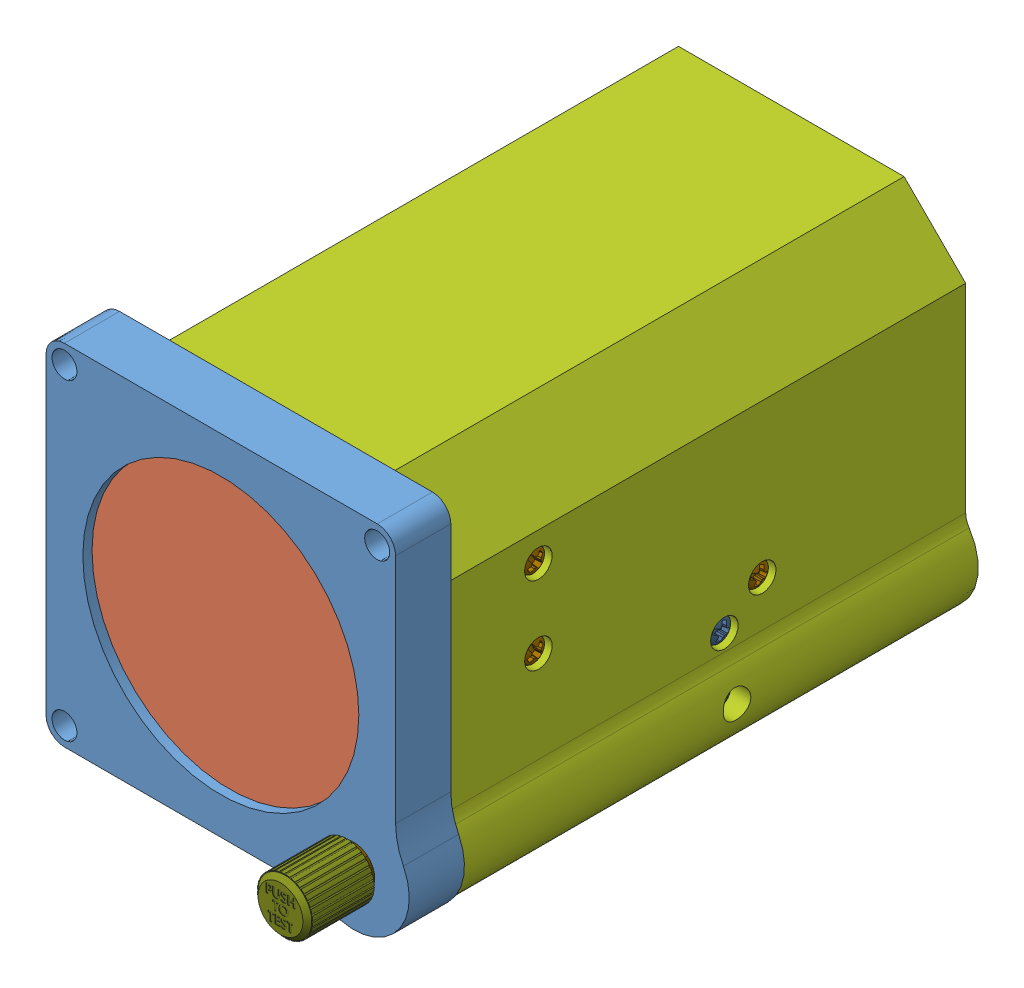
SolidWorks assembly Radar Altimeter, configuration Default. Lengths in mm.
Overall size (63.84 62.68 111.12).
82 component instances, 36 part files, 162 mates.
Components (placement in the parent):
- Radar Altimeter Bezel-1: Radar Altimeter Bezel [Default] at origin size (62.68 62.68 9.53)
- Airspeed Indicator Cover Glass-1: Airspeed Indicator Cover Glass [Default] at (0 0 6.35) size (49.91 49.91 1.59)
- Radar Altimeter Needle Mask-1: Radar Altimeter Needle Mask [Default] at (0 0 3.175) size (49.91 49.91 3.17)
- Radar Altimeter Dial Face-1: Radar Altimeter Dial Face [Default] at (0 0 -3.175) size (47.65 47.65 1.59)
- Radar Altimeter Stepper Mount-1: Radar Altimeter Stepper Mount [Default] at (0 0 -3.175) x (-1 0 0) z (0 0 -1) size (54.44 52.43 10.49)
- Radar Altimeter Stepper Standoff-1: Radar Altimeter Stepper Standoff [Default] at (0 0 -3.175) x (-1 0 0) z (0 0 -1) size (56.62 55.62 12.7)
- Radar Altimeter Case-1: Radar Altimeter Case [Default] x (-1 0 0) z (0 0 -1) size (62.36 61.36 88.9)
- Radar Altimeter Indicator Pointer-1: Radar Altimeter Indicator Pointer [Default] at origin size (6.35 21.41 0.76)
- VID29-02-1: VID29-02 [Default] at (0 6 -17.188) x (1 0 0) z (0 -1 0) size (31.7 22.35 29.3)
- MD-80PL100-1: MD-80PL100 [Default] at (0 -8.7668 -85.09) x (0 0 -1) z (1 0 0) size (21.05 14 25)
- MD-40PL100-1: MD-40PL100 [Default] at (0 9.7828 -85.09) x (0 0 -1) z (1 0 0) size (21.05 14 25)
- SMB 200 RTP-1: SMB 200 RTP [Default] at (-9.525 0 -7.3279) x (0 0 -1) z (1 0 0) size (7.24 4.9 4.98)
- LTW-420D7-1: LTW-420D7 [Default] at (-9.525 0 -6.5659) x (-1 0 0) z (0 1 0) size (3.4 10.4 3.8)
- SMB 200 GTP-1: SMB 200 GTP [Default] at (9.525 0 -7.3279) x (0 0 -1) z (0.923728 0.383049 0) size (7.24 4.9 4.98)
- LTW-420D7-2: LTW-420D7 [Default] at (9.525 0 -6.5659) x (-1 0 0) z (0 1 0) size (3.4 10.4 3.8)
- Radar Altimeter Limit Indexer Ring-1: Radar Altimeter Limit Indexer Ring [Default] x (0 -1 0) z (0 0 1) size (54.8 54.8 4.19)
- Radar Altimeter Knob-1: Radar Altimeter Knob [Default] at (22.9895 -22.9895 9.525) x (1 0 0) z (0 -1 0) size (9.52 11.43 9.52)
- Radar Altimeter Limit Shaft Gear-2: Radar Altimeter Limit Shaft Gear [Default] at (22.9895 -22.9895 -3.1496) x (-1 0 0) z (0 0 1) size (13.89 13.89 6.35)
- 634070_SERVOCITY_.250 X 2.250 D-SHAFT-1: 634070_SERVOCITY_.250 X 2.250 D-SHAFT [Default] at (22.9895 -22.9895 -9.398) x (-1 0 0) z (0 -1 0) size (6.34 57.15 5.59)
- 6630S0D-C28-A103 -1: 6630S0D-C28-A103  [Default] at (13.037 -15.1003 -67.0052) size (22.23 22.23 41.93)
- 615242_SERVOCITY_GEAR_.250 SHAFT-1: 615242_SERVOCITY_GEAR_.250 SHAFT [Default] at (-12.7042 12.8762 11.5787) x (-1 0 0) z (0 0 -1) size (14.29 14.29 12.89)
  - 615242_Gear Blank-1: 615242_Gear Blank [Default] at (-35.6936 -35.8657 43.2017) size (14.29 14.29 12.7)
  - 632134_91375A436-1: 632134_91375A436 [Default] at (-35.6936 -31.9694 40.0267) x (0.866032 0 0.499989) z (0 1 0) size (4.98 4.83 3.31)
- 615242_SERVOCITY_GEAR_.250 SHAFT-2: 615242_SERVOCITY_GEAR_.250 SHAFT [Default] at (48.7306 20.7654 -81.1747) size (14.29 14.29 12.89)
  - 615242_Gear Blank-1: 615242_Gear Blank [Default] at (-35.6936 -35.8657 43.2017) size (14.29 14.29 12.7)
  - 632134_91375A436-1: 632134_91375A436 [Default] at (-35.6936 -31.9694 40.0267) x (0.866032 0 0.499989) z (0 1 0) size (4.98 4.83 3.31)
- 1692K530_TYPE 302 SS CONICAL COMPRESSION SPRING-1: 1692K530_TYPE 302 SS CONICAL COMPRESSION SPRING [1692K53] at (22.9895 -22.9895 -8.824) x (-0.923728 -0.383049 0) z (-0.383049 0.923728 0) size (11.69 5.68 11.52)
- 7658K170_SUBMINIATURE SNAP-ACTING SWITCH-2: 7658K170_SUBMINIATURE SNAP-ACTING SWITCH [Default] at (23.9673 -17.7927 -49.6316) x (0 1 0) z (1 0 0) size (19.99 14.86 6.5)
- Radar Altimeter Pot Mount-1: Radar Altimeter Pot Mount [Default] at (13.037 -15.1003 -56.9722) size (25.29 22.23 12.7)
- 90760A005_ZINC PLATED STEEL NARROW HEX NUT-1: 90760A005_ZINC PLATED STEEL NARROW HEX NUT [Default] at (19.9223 -13.0048 -47.2694) x (0 -0.557681 -0.830056) z (0 0.830056 -0.557681) size (4.76 1.76 5.5)
- 90760A005_ZINC PLATED STEEL NARROW HEX NUT-2: 90760A005_ZINC PLATED STEEL NARROW HEX NUT [Default] at (19.9223 -22.6441 -47.2694) x (0 -0.557681 -0.830056) z (0 0.830056 -0.557681) size (4.76 1.76 5.5)
- 93365A110_BRASS HEAT-SET INSERT FOR PLASTICS_2-56-6: 93365A110_BRASS HEAT-SET INSERT FOR PLASTICS_2-56 [Default] at (5.0486 -26.2128 -47.4472) x (-0.133778 0 -0.991011) z (-0.991011 0 0.133778) size (3.58 3.09 3.58)
- 90272A077_ZINC-PLTD STL PAN HEAD PHILLIPS MACHINE SCREW_2-56 X .250-5: 90272A077_ZINC-PLTD STL PAN HEAD PHILLIPS MACHINE SCREW_2-56 X .250 [90272A077] at (5.0486 -20.9042 -47.4472) x (0.315604 0 0.948891) z (0 -1 0) size (4.24 4.24 7.94)
- 93365A110_BRASS HEAT-SET INSERT FOR PLASTICS_2-56-19: 93365A110_BRASS HEAT-SET INSERT FOR PLASTICS_2-56 [Default] at (27.2185 -7.9566 -53.7972) x (0 -0.1618 -0.986824) z (0 -0.986824 0.1618) size (3.58 3.09 3.58)
- 90272A077_ZINC-PLTD STL PAN HEAD PHILLIPS MACHINE SCREW_2-56 X .250-7: 90272A077_ZINC-PLTD STL PAN HEAD PHILLIPS MACHINE SCREW_2-56 X .250 [90272A077] at (21.9099 -7.9566 -53.7972) x (0 0.34236 0.939569) z (1 0 0) size (4.24 4.24 7.94)
- 90272A079_ZINC-PLTD STL PAN HEAD PHILLIPS MACHINE SCREW_2-56 X .375-11: 90272A079_ZINC-PLTD STL PAN HEAD PHILLIPS MACHINE SCREW_2-56 X .375 [90272A079] at (18.7349 -13.0048 -47.2694) x (0 -0.383049 -0.923728) z (1 0 0) size (4.24 4.24 11.11)
- 90272A079_ZINC-PLTD STL PAN HEAD PHILLIPS MACHINE SCREW_2-56 X .375-12: 90272A079_ZINC-PLTD STL PAN HEAD PHILLIPS MACHINE SCREW_2-56 X .375 [90272A079] at (18.7349 -22.6441 -47.2694) x (0 -0.231744 -0.972777) z (1 0 0) size (4.24 4.24 11.11)
- Hitec Ultra Nano HS-35HD-1: Hitec Ultra Nano HS-35HD [Default] at (1.8656 -35.3668 -24.7523) x (0.579498 -0.814974 0) z (0 0 1) size (25.28 28.66 21.31)
  - Hitec HS-35HD Ultra Nano Servo-1: Hitec HS-35HD Ultra Nano Servo [Default] at (-26.6145 -7.4096 -0.762) x (0.579498 0.814974 0) z (0 0 1) size (26.49 7.75 19.66)
  - servo horn-1: servo horn [Default] at (-27.1584 -1.5999 19.9898) x (0.728983 0.684532 0) z (-0.684532 0.728983 0) size (16.38 3.21 16.38)
  - screw-1: screw [Default] at (-27.1584 -1.5999 20.5457) x (0.992399 -0.123063 0) z (0 0 1) size (2.9 2.9 4.67)
- Radar Altimeter OFF Flag-2: Radar Altimeter OFF Flag [Default] at (0 0 -3.175) x (-1 0 0) z (0 0 -1) size (30.35 16.38 1.59)
- 92671A115_BRASS HEX NUT-1: 92671A115_BRASS HEX NUT [92671A115] at (1.143 -14.1605 -8.2297) x (0.956133 -0.292934 0) z (-0.292934 -0.956133 0) size (3.97 1.51 4.58)
- 92671A115_BRASS HEX NUT-2: 92671A115_BRASS HEX NUT [92671A115] at (-21.59 -14.1605 -8.2297) x (0.990484 -0.137631 0) z (-0.137631 -0.990484 0) size (3.97 1.51 4.58)
- 91772A061_18-8 SS PAN HEAD PHILLIPS MACHINE SCREW_#0-80 X .2812-1: 91772A061_18-8 SS PAN HEAD PHILLIPS MACHINE SCREW_#0-80 X .2812 [91772A061] at (-21.59 -14.1605 -7.0421) x (-0.923728 -0.383049 0) z (0 0 -1) size (2.95 2.95 8.26)
- 91772A061_18-8 SS PAN HEAD PHILLIPS MACHINE SCREW_#0-80 X .2812-2: 91772A061_18-8 SS PAN HEAD PHILLIPS MACHINE SCREW_#0-80 X .2812 [91772A061] at (1.143 -14.1605 -7.0421) x (-0.85131 -0.524663 0) z (0 0 -1) size (2.95 2.95 8.26)
- 93365A110_BRASS HEAT-SET INSERT FOR PLASTICS_2-56-1: 93365A110_BRASS HEAT-SET INSERT FOR PLASTICS_2-56 [Default] at (20.6092 18.5346 -8.825) x (-0.984497 -0.175399 0) z (0.175399 -0.984497 0) size (3.58 3.09 3.58)
- 93365A110_BRASS HEAT-SET INSERT FOR PLASTICS_2-56-18: 93365A110_BRASS HEAT-SET INSERT FOR PLASTICS_2-56 [Default] at (-20.6092 -4.5 -8.825) x (-0.984497 -0.175399 0) z (0.175399 -0.984497 0) size (3.58 3.09 3.58)
- 93365A110_BRASS HEAT-SET INSERT FOR PLASTICS_2-56-4: 93365A110_BRASS HEAT-SET INSERT FOR PLASTICS_2-56 [Default] at (-20.6092 18.5346 -8.825) x (-0.984497 -0.175399 0) z (0.175399 -0.984497 0) size (3.58 3.09 3.58)
- 90272A079_ZINC-PLTD STL PAN HEAD PHILLIPS MACHINE SCREW_2-56 X .375-4: 90272A079_ZINC-PLTD STL PAN HEAD PHILLIPS MACHINE SCREW_2-56 X .375 [90272A079] at (20.6092 18.5346 -4.0752) x (-0.923728 -0.383049 0) z (0 0 -1) size (4.24 4.24 11.11)
- 90272A079_ZINC-PLTD STL PAN HEAD PHILLIPS MACHINE SCREW_2-56 X .375-10: 90272A079_ZINC-PLTD STL PAN HEAD PHILLIPS MACHINE SCREW_2-56 X .375 [90272A079] at (-20.6092 -4.5 -4.0752) x (-0.923728 -0.383049 0) z (0 0 -1) size (4.24 4.24 11.11)
- 90272A079_ZINC-PLTD STL PAN HEAD PHILLIPS MACHINE SCREW_2-56 X .375-5: 90272A079_ZINC-PLTD STL PAN HEAD PHILLIPS MACHINE SCREW_2-56 X .375 [90272A079] at (-20.6092 18.5346 -4.0752) x (-0.923728 -0.383049 0) z (0 0 -1) size (4.24 4.24 11.11)
- 93365A110_BRASS HEAT-SET INSERT FOR PLASTICS_2-56-2: 93365A110_BRASS HEAT-SET INSERT FOR PLASTICS_2-56 [Default] at (-27.2185 13.456 -15.175) x (0 -0.185827 -0.982583) z (0 0.982583 -0.185827) size (3.58 3.09 3.58)
- 90272A077_ZINC-PLTD STL PAN HEAD PHILLIPS MACHINE SCREW_2-56 X .250-4: 90272A077_ZINC-PLTD STL PAN HEAD PHILLIPS MACHINE SCREW_2-56 X .250 [90272A077] at (-21.9099 13.456 -15.175) x (0 0 1) z (-1 0 0) size (4.24 4.24 7.94)
- 93365A110_BRASS HEAT-SET INSERT FOR PLASTICS_2-56-15: 93365A110_BRASS HEAT-SET INSERT FOR PLASTICS_2-56 [Default] at (25.4059 16.1162 0) x (0.880537 0.473977 0) z (-0.473977 0.880537 0) size (3.58 3.09 3.58)
- 93365A110_BRASS HEAT-SET INSERT FOR PLASTICS_2-56-17: 93365A110_BRASS HEAT-SET INSERT FOR PLASTICS_2-56 [Default] at (-25.4059 16.1162 0) x (0.880537 0.473977 0) z (-0.473977 0.880537 0) size (3.58 3.09 3.58)
- 90272A079_ZINC-PLTD STL PAN HEAD PHILLIPS MACHINE SCREW_2-56 X .375-7: 90272A079_ZINC-PLTD STL PAN HEAD PHILLIPS MACHINE SCREW_2-56 X .375 [90272A079] at (25.4059 16.1162 3.5448) x (0.258691 -0.96596 0) z (0 0 -1) size (4.24 4.24 11.11)
- 90272A079_ZINC-PLTD STL PAN HEAD PHILLIPS MACHINE SCREW_2-56 X .375-9: 90272A079_ZINC-PLTD STL PAN HEAD PHILLIPS MACHINE SCREW_2-56 X .375 [90272A079] at (-25.4059 16.1162 3.5448) x (0.258691 -0.96596 0) z (0 0 -1) size (4.24 4.24 11.11)
- 93365A110_BRASS HEAT-SET INSERT FOR PLASTICS_2-56-20: 93365A110_BRASS HEAT-SET INSERT FOR PLASTICS_2-56 [Default] at (-27.2185 0 -15.175) x (0 -0.027685 -0.999617) z (0 0.999617 -0.027685) size (3.58 3.09 3.58)
- 90272A077_ZINC-PLTD STL PAN HEAD PHILLIPS MACHINE SCREW_2-56 X .250-8: 90272A077_ZINC-PLTD STL PAN HEAD PHILLIPS MACHINE SCREW_2-56 X .250 [90272A077] at (-21.9099 0 -15.175) x (0 -0.158553 0.987351) z (-1 0 0) size (4.24 4.24 7.94)
- 93365A110_BRASS HEAT-SET INSERT FOR PLASTICS_2-56-21: 93365A110_BRASS HEAT-SET INSERT FOR PLASTICS_2-56 [Default] at (-14.4616 -26.2128 -15.175) x (-0.396628 0 -0.91798) z (-0.91798 0 0.396628) size (3.58 3.09 3.58)
- 90272A077_ZINC-PLTD STL PAN HEAD PHILLIPS MACHINE SCREW_2-56 X .250-9: 90272A077_ZINC-PLTD STL PAN HEAD PHILLIPS MACHINE SCREW_2-56 X .250 [90272A077] at (-14.4616 -20.9042 -15.175) x (0.560305 0 0.828287) z (0 -1 0) size (4.24 4.24 7.94)
- 93365A110_BRASS HEAT-SET INSERT FOR PLASTICS_2-56-22: 93365A110_BRASS HEAT-SET INSERT FOR PLASTICS_2-56 [Default] at (11.1826 -26.2128 -13.389) x (-0.600122 0 -0.799909) z (-0.799909 0 0.600122) size (3.58 3.09 3.58)
- 90272A077_ZINC-PLTD STL PAN HEAD PHILLIPS MACHINE SCREW_2-56 X .250-10: 90272A077_ZINC-PLTD STL PAN HEAD PHILLIPS MACHINE SCREW_2-56 X .250 [90272A077] at (11.1826 -20.9042 -13.389) x (0.738314 0 0.674458) z (0 -1 0) size (4.24 4.24 7.94)
- 93365A110_BRASS HEAT-SET INSERT FOR PLASTICS_2-56-23: 93365A110_BRASS HEAT-SET INSERT FOR PLASTICS_2-56 [Default] at (27.2185 13.456 -15.175) x (0 -0.622542 -0.782586) z (0 -0.782586 0.622542) size (3.58 3.09 3.58)
- 90272A077_ZINC-PLTD STL PAN HEAD PHILLIPS MACHINE SCREW_2-56 X .250-11: 90272A077_ZINC-PLTD STL PAN HEAD PHILLIPS MACHINE SCREW_2-56 X .250 [90272A077] at (21.9099 13.456 -15.175) x (0 0.757125 0.65327) z (1 0 0) size (4.24 4.24 7.94)
- 93365A110_BRASS HEAT-SET INSERT FOR PLASTICS_2-56-24: 93365A110_BRASS HEAT-SET INSERT FOR PLASTICS_2-56 [Default] at (27.2185 0 -15.175) x (0 -0.682826 -0.730581) z (0 -0.730581 0.682826) size (3.58 3.09 3.58)
- 90272A077_ZINC-PLTD STL PAN HEAD PHILLIPS MACHINE SCREW_2-56 X .250-12: 90272A077_ZINC-PLTD STL PAN HEAD PHILLIPS MACHINE SCREW_2-56 X .250 [90272A077] at (21.9099 0 -15.175) x (0 0.806695 0.590969) z (1 0 0) size (4.24 4.24 7.94)
- 93365A102 - INSERT, 0-80, BRASS, FOR PLASTICS-1: 93365A102 - INSERT, 0-80, BRASS, FOR PLASTICS [Default] at (-9.5 -8.7668 -85.09) x (1 0 0) z (0 -1 0) size (3.58 3.01 3.58)
- 93365A102 - INSERT, 0-80, BRASS, FOR PLASTICS-2: 93365A102 - INSERT, 0-80, BRASS, FOR PLASTICS [Default] at (9.5 -8.7668 -85.09) x (0.987351 0.158553 0) z (0.158553 -0.987351 0) size (3.58 3.01 3.58)
- 93365A102 - INSERT, 0-80, BRASS, FOR PLASTICS-4: 93365A102 - INSERT, 0-80, BRASS, FOR PLASTICS [Default] at (9.5 9.7828 -85.09) x (0.959125 0.282984 0) z (0.282984 -0.959125 0) size (3.58 3.01 3.58)
- 93365A102 - INSERT, 0-80, BRASS, FOR PLASTICS-6: 93365A102 - INSERT, 0-80, BRASS, FOR PLASTICS [Default] at (-9.5 9.7828 -85.09) x (0.928571 0.371154 0) z (0.371154 -0.928571 0) size (3.58 3.01 3.58)
- 91772A064 - PHS, 0-80 x .4375, 18-8-1: 91772A064 - PHS, 0-80 x .4375, 18-8 [91772A064] at (-9.5 9.7828 -88.2025) x (-0.994753 -0.10231 0) z (0 0 1) size (2.95 2.95 12.24)
- 91772A064 - PHS, 0-80 x .4375, 18-8-2: 91772A064 - PHS, 0-80 x .4375, 18-8 [91772A064] at (9.5 9.7828 -88.2025) x (-0.965948 -0.258737 0) z (0 0 1) size (2.95 2.95 12.24)
- 91772A064 - PHS, 0-80 x .4375, 18-8-4: 91772A064 - PHS, 0-80 x .4375, 18-8 [91772A064] at (-9.5 -8.7668 -88.2025) x (-0.92514 -0.379627 0) z (0 0 1) size (2.95 2.95 12.24)
- 91772A064 - PHS, 0-80 x .4375, 18-8-6: 91772A064 - PHS, 0-80 x .4375, 18-8 [91772A064] at (9.5 -8.7668 -88.2025) x (-0.885726 -0.464208 0) z (0 0 1) size (2.95 2.95 12.24)
- 93365A102 - INSERT, 0-80, BRASS, FOR PLASTICS-8: 93365A102 - INSERT, 0-80, BRASS, FOR PLASTICS [Default] at (13.5 6 -10.488) x (-0.173648 0.984808 0) z (-0.984808 -0.173648 0) size (3.58 3.01 3.58)
- 93365A102 - INSERT, 0-80, BRASS, FOR PLASTICS-10: 93365A102 - INSERT, 0-80, BRASS, FOR PLASTICS [Default] at (-13.5 6 -10.488) x (-0.34202 0.939693 0) z (-0.939693 -0.34202 0) size (3.58 3.01 3.58)
- 91772A064 - PHS, 0-80 x .4375, 18-8-8: 91772A064 - PHS, 0-80 x .4375, 18-8 [91772A064] at (13.5 6 -6.3755) x (0.965948 -0.258737 0) z (0 0 -1) size (2.95 2.95 12.24)
- 91772A064 - PHS, 0-80 x .4375, 18-8-10: 91772A064 - PHS, 0-80 x .4375, 18-8 [91772A064] at (-13.5 6 -6.3755) x (-0.92514 0.379627 0) z (0 0 -1) size (2.95 2.95 12.24)
- 93365A110_BRASS HEAT-SET INSERT FOR PLASTICS_2-56-28: 93365A110_BRASS HEAT-SET INSERT FOR PLASTICS_2-56 [Default] at (20.6092 -4.5 -8.825) x (-0.984497 -0.175399 0) z (0.175399 -0.984497 0) size (3.58 3.09 3.58)
- 90272A079_ZINC-PLTD STL PAN HEAD PHILLIPS MACHINE SCREW_2-56 X .375-13: 90272A079_ZINC-PLTD STL PAN HEAD PHILLIPS MACHINE SCREW_2-56 X .375 [90272A079] at (20.6092 -4.5 -4.0752) x (-0.923728 -0.383049 0) z (0 0 -1) size (4.24 4.24 11.11)
Mates (geometry in assembly coordinates):
- InPlace1: in place: plane of ? through (0 0 0) normal (0 0 1); moOrthogonalPlaneRef_w of ? through (0 0 0) normal (0 1 0); plane of ? through (0 0 0) normal (1 0 0); unknown of ?
- Coincident1: coincident aligned: 
- Coincident2: coincident aligned: plane of Radar Altimeter Bezel-1 through (0 0 0) normal (0 1 0)
- Coincident3: coincident anti-aligned: plane of Radar Altimeter Bezel-1 through (0 0 0) normal (1 0 0)
- Concentric1: concentric aligned: cylinder of Radar Altimeter Bezel-1 through (0 0 81.1874) axis (0 0 -1) radius 25.3365; cylinder of Airspeed Indicator Cover Glass-1 through (0 0 7.9375) axis (0 0 -1) radius 24.9555
- Coincident1: coincident anti-aligned: plane of Radar Altimeter Bezel-1 through (0 0 7.9375) normal (0 0 -1); plane of Airspeed Indicator Cover Glass-1 through (0 0 7.9375) normal (0 0 1)
- Concentric2: concentric aligned: cylinder of Radar Altimeter Bezel-1 through (0 0 81.1874) axis (0 0 -1) radius 25.3365; cylinder of Radar Altimeter Needle Mask-1 through (0 0 6.35) axis (0 0 -1) radius 24.9555
- Concentric5: concentric aligned: cylinder of Radar Altimeter Bezel-1 through (0 0 81.1874) axis (0 0 -1) radius 25.3365; cylinder of Radar Altimeter Dial Face-1 through (0 0 -1.5875) axis (0 0 -1) radius 23.8252
- Parallel1: parallel aligned: plane of Radar Altimeter Bezel-1 through (30.1625 0 9.525) normal (1 0 0); plane of Radar Altimeter Dial Face-1 through (0 0 -3.175) normal (1 0 0)
- Coincident7: coincident anti-aligned: plane of Radar Altimeter Dial Face-1 through (0 0 -3.175) normal (0 0 -1); plane of Radar Altimeter Stepper Mount-1 through (0 0 -3.175) normal (0 0 1)
- Parallel2: parallel anti-aligned: plane of Radar Altimeter Bezel-1 through (30.1625 0 9.525) normal (1 0 0); plane of Radar Altimeter Stepper Mount-1 through (0 0 -3.175) normal (-1 0 0)
- Distance1: distance = 1.5875 mm anti-aligned: plane of Radar Altimeter Indicator Pointer-1 through (0 0 0) normal (0 0 -1); plane of Radar Altimeter Dial Face-1 through (0 0 -1.5875) normal (0 0 1)
- Width12: width anti-aligned: plane of Radar Altimeter Stepper Mount-1 through (-18.2716 26.2128 -100.9823) normal (0 1 0); plane of Radar Altimeter Stepper Mount-1 through (16.2895 -26.2128 -100.9823) normal (0 -1 0); plane of Radar Altimeter Bezel-1 through (0 -30.1625 9.525) normal (0 -1 0); plane of Radar Altimeter Bezel-1 through (0 30.1625 9.525) normal (0 1 0)
- Concentric55: concentric aligned: cone of Radar Altimeter Stepper Mount-1 through (20.6092 18.5346 -8.825) axis (0 0 1); cone of 93365A110_BRASS HEAT-SET INSERT FOR PLASTICS_2-56-1 through (20.6092 18.5346 -7.715) axis (0 0 1)
- Coincident81: coincident aligned: plane of Radar Altimeter Stepper Mount-1 through (0 -6 -8.825) normal (0 0 -1); plane of 93365A110_BRASS HEAT-SET INSERT FOR PLASTICS_2-56-1 through (22.3722 18.8487 -8.825) normal (0 0 -1)
- Concentric80: concentric anti-aligned: cylinder of SMB 200 RTP-1 through (-9.525 0 -0.0889) axis (0 0 1) radius 2.1947; cylinder of LTW-420D7-1 through (-9.525 0 -6.5659) axis (0 0 -1) radius 1.5
- Parallel31: parallel anti-aligned: plane of Radar Altimeter Bezel-1 through (0 30.1625 9.525) normal (0 1 0); plane of LTW-420D7-1 through (-10.5629 -0.1492 -10.5659) normal (0 -1 0)
- Distance7: distance = 0.762 mm aligned: plane of LTW-420D7-1 through (-9.525 0 -6.5659) normal (0 0 -1); plane of SMB 200 RTP-1 through (-9.525 -2.1844 -7.3279) normal (0 0 -1)
- Concentric81: concentric aligned: cylinder of Radar Altimeter Dial Face-1 through (-9.525 0 -1.5875) axis (0 0 1) radius 2.1829; cylinder of SMB 200 RTP-1 through (-9.525 0 -0.0889) axis (0 0 1) radius 2.4511
- Coincident113: coincident anti-aligned: plane of Radar Altimeter Dial Face-1 through (0 0 -1.5875) normal (0 0 1); plane of SMB 200 RTP-1 through (-9.525 -2.1947 -1.5875) normal (0 0 -1)
- Concentric82: concentric aligned: cylinder of Radar Altimeter Dial Face-1 through (9.525 0 -1.5875) axis (0 0 1) radius 2.1829; cylinder of SMB 200 GTP-1 through (9.525 0 -0.0889) axis (0 0 1) radius 2.1947
- Coincident114: coincident anti-aligned: plane of Radar Altimeter Dial Face-1 through (0 0 -1.5875) normal (0 0 1); plane of SMB 200 GTP-1 through (10.3657 -2.0273 -1.5875) normal (0 0 -1)
- Concentric83: concentric anti-aligned: cylinder of SMB 200 GTP-1 through (9.525 0 -0.0889) axis (0 0 1) radius 2.1947; cylinder of LTW-420D7-2 through (9.525 0 -6.5659) axis (0 0 -1) radius 1.5
- Coincident115: coincident aligned: plane of LTW-420D7-1 through (-9.525 0 -6.5659) normal (0 0 -1); plane of LTW-420D7-2 through (9.525 0 -6.5659) normal (0 0 -1)
- Coincident116: coincident aligned: plane of LTW-420D7-1 through (-8.4871 -0.1492 -10.5659) normal (0 -1 0); plane of LTW-420D7-2 through (10.5629 -0.1492 -10.5659) normal (0 -1 0)
- Coincident117: coincident anti-aligned: plane of Airspeed Indicator Cover Glass-1 through (0 0 6.35) normal (0 0 -1); plane of Radar Altimeter Needle Mask-1 through (0 0 6.35) normal (0 0 1)
- Concentric86: concentric aligned: cylinder of Radar Altimeter Needle Mask-1 through (0 0 6.35) axis (0 0 -1) radius 23.368; cylinder of Radar Altimeter Limit Indexer Ring-1 through (0 0 -1.016) axis (0 0 -1) radius 23.368
- Coincident125: coincident aligned: plane of Radar Altimeter Limit Indexer Ring-1 through (0 0 0) normal (0 0 -1); plane of Radar Altimeter Limit Shaft Gear-2 through (22.9895 -22.9895 -3.1496) normal (0 0 -1)
- Coincident129: coincident anti-aligned: plane of Radar Altimeter Bezel-1 through (0 0 3.2004) normal (0 0 -1); plane of Radar Altimeter Limit Shaft Gear-2 through (22.9895 -22.9895 3.2004) normal (0 0 1)
- Coincident131: coincident anti-aligned: plane of Radar Altimeter Bezel-1 through (0 0 0) normal (0 0 -1); plane of Radar Altimeter Stepper Mount-1 through (28.4885 -15.4695 0) normal (0 0 1)
- Parallel36: parallel aligned: plane of Radar Altimeter Bezel-1 through (-30.1625 0 9.525) normal (-1 0 0); plane of Radar Altimeter Indicator Pointer-1 through (-1.1811 2.9471 0.762) normal (-1 0 0)
- Concentric94: concentric aligned: cone of Radar Altimeter Bezel-1 through (25.4059 16.1162 0) axis (0 0 1); cone of 93365A110_BRASS HEAT-SET INSERT FOR PLASTICS_2-56-15 through (25.4059 16.1162 1.11) axis (0 0 1)
- Coincident138: coincident aligned: plane of Radar Altimeter Bezel-1 through (0 0 0) normal (0 0 -1); plane of 93365A110_BRASS HEAT-SET INSERT FOR PLASTICS_2-56-15 through (23.8292 15.2674 0) normal (0 0 -1)
- Concentric95: concentric anti-aligned: circle of 93365A110_BRASS HEAT-SET INSERT FOR PLASTICS_2-56-15; cylinder of 90272A079_ZINC-PLTD STL PAN HEAD PHILLIPS MACHINE SCREW_2-56 X .375-7 through (25.4059 16.1162 3.5448) axis (0 0 1) radius 2.1209
- Coincident139: coincident anti-aligned: plane of Radar Altimeter Stepper Mount-1 through (24.0534 16.1162 -5.9802) normal (0 0 -1); plane of 90272A079_ZINC-PLTD STL PAN HEAD PHILLIPS MACHINE SCREW_2-56 X .375-7 through (25.4059 16.1162 -5.9802) normal (0 0 1)
- Coincident143: coincident aligned: plane of Radar Altimeter Stepper Mount-1 through (27.2185 17.266 -100.9823) normal (1 0 0); plane of Radar Altimeter Stepper Standoff-1 through (27.2185 -7.2568 -97.1016) normal (1 0 0)
- Coincident144: coincident aligned: plane of Radar Altimeter Stepper Mount-1 through (-18.2716 26.2128 -100.9823) normal (0 1 0); plane of Radar Altimeter Stepper Standoff-1 through (18.2716 26.2128 -97.1016) normal (0 1 0)
- Coincident145: coincident anti-aligned: plane of Radar Altimeter Stepper Mount-1 through (0 -6 -8.825) normal (0 0 -1); plane of Radar Altimeter Stepper Standoff-1 through (0 0 -8.825) normal (0 0 1)
- Concentric97: concentric anti-aligned: cylinder of Radar Altimeter Bezel-1 through (22.9895 -22.9895 9.525) axis (0 0 1) radius 3.5712; cylinder of Radar Altimeter Limit Shaft Gear-2 through (22.9895 -22.9895 3.2004) axis (0 0 -1) radius 3.4226
- Concentric99: concentric anti-aligned: cylinder of Radar Altimeter Stepper Standoff-1 through (22.9895 -22.9895 22.3754) axis (0 0 -1) radius 3.2385; cylinder of 634070_SERVOCITY_.250 X 2.250 D-SHAFT-1 through (22.9895 -22.9895 -37.973) axis (0 0 1) radius 3.1686
- Parallel38: parallel anti-aligned: plane of Radar Altimeter Limit Shaft Gear-2 through (20.8491 -20.3186 3.2004) normal (0 -1 0); plane of 634070_SERVOCITY_.250 X 2.250 D-SHAFT-1 through (25.0387 -20.5726 -37.973) normal (0 1 0)
- Coincident147: coincident anti-aligned: plane of Radar Altimeter Knob-1 through (22.9895 -22.9895 19.177) normal (0 0 -1); plane of 634070_SERVOCITY_.250 X 2.250 D-SHAFT-1 through (22.9895 -22.9895 19.177) normal (0 0 1)
- Parallel40: parallel aligned: plane of Radar Altimeter Bezel-1 through (0 30.1625 9.525) normal (0 1 0); plane of 634070_SERVOCITY_.250 X 2.250 D-SHAFT-1 through (25.0387 -20.5726 -37.973) normal (0 1 0)
- Parallel41: parallel anti-aligned: plane of 634070_SERVOCITY_.250 X 2.250 D-SHAFT-1 through (25.0387 -20.5726 -37.973) normal (0 1 0); plane of 6630S0D-C28-A103 -1 through (8.3126 -17.4663 -34.798) normal (0 -1 0)
- Concentric101: concentric anti-aligned: cylinder of 634070_SERVOCITY_.250 X 2.250 D-SHAFT-1 through (22.9895 -22.9895 -37.973) axis (0 0 1) radius 3.1686; cylinder of 615242_SERVOCITY_GEAR_.250 SHAFT-1/615242_Gear Blank-1 through (22.9895 -22.9895 -25.273) axis (0 0 -1) radius 3.175
- Parallel42: parallel aligned: plane of 634070_SERVOCITY_.250 X 2.250 D-SHAFT-1 through (25.0387 -20.5726 -37.973) normal (0 1 0); plane of 615242_SERVOCITY_GEAR_.250 SHAFT-1/632134_91375A436-1 through (22.9895 -17.9029 -28.448) normal (0 1 0)
- Coincident152: coincident aligned: plane of 634070_SERVOCITY_.250 X 2.250 D-SHAFT-1 through (22.9895 -22.9895 -37.973) normal (0 0 -1); plane of 615242_SERVOCITY_GEAR_.250 SHAFT-1/615242_Gear Blank-1 through (23.4471 -16.2138 -37.973) normal (0 0 -1)
- Concentric102: concentric aligned: cylinder of 6630S0D-C28-A103 -1 through (13.037 -15.1003 -58.547) axis (0 0 1) radius 3.1712; cylinder of 615242_SERVOCITY_GEAR_.250 SHAFT-2/615242_Gear Blank-1 through (13.037 -15.1003 -44.323) axis (0 0 1) radius 3.175
- Parallel43: parallel anti-aligned: plane of 6630S0D-C28-A103 -1 through (8.3126 -17.4663 -34.798) normal (0 -1 0); plane of 615242_SERVOCITY_GEAR_.250 SHAFT-2/632134_91375A436-1 through (13.037 -10.0138 -41.148) normal (0 1 0)
- Distance12: distance = 3.175 mm aligned: plane of 6630S0D-C28-A103 -1 through (13.037 -15.1003 -34.798) normal (0 0 1); plane of 615242_SERVOCITY_GEAR_.250 SHAFT-2/615242_Gear Blank-1 through (12.5793 -8.3247 -31.623) normal (0 0 1)
- Concentric104: concentric aligned: cylinder of 634070_SERVOCITY_.250 X 2.250 D-SHAFT-1 through (22.9895 -22.9895 -37.973) axis (0 0 1) radius 3.1686; line of 1692K530_TYPE 302 SS CONICAL COMPRESSION SPRING-1 through (22.9895 -22.9895 -9.2204) axis (0 0 1)
- Coincident155: coincident anti-aligned: plane of Radar Altimeter Limit Shaft Gear-2 through (22.9895 -22.9895 -3.1496) normal (0 0 -1); plane of 1692K530_TYPE 302 SS CONICAL COMPRESSION SPRING-1 through (22.9895 -22.9895 -3.1496) normal (0 0 1)
- Concentric105: concentric anti-aligned: cylinder of Radar Altimeter Stepper Standoff-1 through (20.6092 18.5346 -21.525) axis (0 0 -1) radius 2.3813; cylinder of 90272A079_ZINC-PLTD STL PAN HEAD PHILLIPS MACHINE SCREW_2-56 X .375-4 through (20.6092 18.5346 -4.0752) axis (0 0 1) radius 2.1209
- Coincident156: coincident anti-aligned: plane of Radar Altimeter Stepper Standoff-1 through (19.2567 18.5346 -13.6002) normal (0 0 -1); plane of 90272A079_ZINC-PLTD STL PAN HEAD PHILLIPS MACHINE SCREW_2-56 X .375-4 through (20.6092 18.5346 -13.6002) normal (0 0 1)
- Parallel44: parallel anti-aligned: plane of Radar Altimeter Stepper Standoff-1 through (-18.2716 -26.2128 -97.1016) normal (0 -1 0); plane of Hitec Ultra Nano HS-35HD-1/Hitec HS-35HD Ultra Nano Servo-1 through (-19.5961 -17.2085 -11.3919) normal (0 1 0)
- InPlace5: in place: plane of Radar Altimeter Dial Face-1 through (0 0 -3.175) normal (0 0 -1); plane of ? through (0 0 -3.175) normal (0 0 -1); plane of Radar Altimeter Dial Face-1 through (0 0 -3.175) normal (0 0 -1); unknown of ?; plane of Radar Altimeter Dial Face-1 through (0 0 -3.175) normal (0 0 -1); plane of ? through (0 0 -3.175) normal (-1 0 0); plane of Radar Altimeter Dial Face-1 through (0 0 -3.175) normal (0 0 -1); unknown of ?
- Coincident158: coincident aligned: plane of Radar Altimeter Dial Face-1; plane of Radar Altimeter OFF Flag-2
- Coincident159: coincident aligned: moOrthogonalPlaneRef_w of Radar Altimeter Dial Face-1 through (0 0 -3.175) normal (0 1 0); plane of Radar Altimeter OFF Flag-2 through (0 0 -3.175) normal (0 1 0)
- Coincident160: coincident anti-aligned: moOrthogonalPlaneRef_w of Radar Altimeter Dial Face-1 through (0 0 -3.175) normal (1 0 0); plane of Radar Altimeter OFF Flag-2 through (0 0 -3.175) normal (-1 0 0)
- Concentric108: concentric aligned: cylinder of Hitec Ultra Nano HS-35HD-1/servo horn-1 through (-15.1765 -14.1605 -7.9756) axis (0 0 1) radius 2.794; cylinder of Radar Altimeter OFF Flag-2 through (-15.1765 -14.1605 -4.7625) axis (0 0 1) radius 8.1915
- Coincident161: coincident anti-aligned: plane of Hitec Ultra Nano HS-35HD-1/servo horn-1 through (-15.1765 -14.1605 -4.7625) normal (0 0 1); plane of Radar Altimeter OFF Flag-2 through (0 0 -4.7625) normal (0 0 -1)
- Concentric110: concentric anti-aligned: cylinder of Radar Altimeter Stepper Standoff-1 through (1.143 -14.1605 -13.1699) axis (0 0 -1) radius 0.9271; circle of 92671A115_BRASS HEX NUT-1
- Coincident162: coincident anti-aligned: plane of Radar Altimeter Stepper Standoff-1 through (0 0 -8.825) normal (0 0 1); plane of 92671A115_BRASS HEX NUT-1 through (-0.4187 -12.4838 -8.825) normal (0 0 -1)
- Concentric111: concentric anti-aligned: cylinder of Radar Altimeter Stepper Standoff-1 through (-21.59 -14.1605 -13.1699) axis (0 0 -1) radius 0.9271; circle of 92671A115_BRASS HEX NUT-2
- Coincident163: coincident anti-aligned: plane of Radar Altimeter Stepper Standoff-1 through (0 0 -8.825) normal (0 0 1); plane of 92671A115_BRASS HEX NUT-2 through (-23.3978 -12.7526 -8.825) normal (0 0 -1)
- Concentric113: concentric aligned: cylinder of Hitec Ultra Nano HS-35HD-1/Hitec HS-35HD Ultra Nano Servo-1 through (-21.59 -14.1605 -25.5143) axis (0 0 1) radius 0.9017; cylinder of 91772A061_18-8 SS PAN HEAD PHILLIPS MACHINE SCREW_#0-80 X .2812-1 through (-21.59 -14.1605 -7.0421) axis (0 0 1) radius 1.4732
- Coincident165: coincident anti-aligned: plane of Hitec Ultra Nano HS-35HD-1/Hitec HS-35HD Ultra Nano Servo-1 through (-19.5961 -17.9705 -14.1859) normal (0 0 -1); plane of 91772A061_18-8 SS PAN HEAD PHILLIPS MACHINE SCREW_#0-80 X .2812-1 through (-21.59 -14.1605 -14.1859) normal (0 0 1)
- Concentric114: concentric aligned: cylinder of Hitec Ultra Nano HS-35HD-1/Hitec HS-35HD Ultra Nano Servo-1 through (1.143 -14.1605 -25.5143) axis (0 0 1) radius 0.9017; cylinder of 91772A061_18-8 SS PAN HEAD PHILLIPS MACHINE SCREW_#0-80 X .2812-2 through (1.143 -14.1605 -7.0421) axis (0 0 1) radius 1.4732
- Coincident166: coincident anti-aligned: plane of Hitec Ultra Nano HS-35HD-1/Hitec HS-35HD Ultra Nano Servo-1 through (-0.8509 -10.3505 -14.1859) normal (0 0 -1); plane of 91772A061_18-8 SS PAN HEAD PHILLIPS MACHINE SCREW_#0-80 X .2812-2 through (1.143 -14.1605 -14.1859) normal (0 0 1)
- Parallel46: parallel anti-aligned: plane of 615242_SERVOCITY_GEAR_.250 SHAFT-1/615242_Gear Blank-1 through (22.9895 -22.9895 -31.623) normal (-1 0 0); plane of 7658K170_SUBMINIATURE SNAP-ACTING SWITCH-2 through (23.9673 -17.7927 -49.6316) normal (1 0 0)
- Parallel45: parallel anti-aligned: plane of 634070_SERVOCITY_.250 X 2.250 D-SHAFT-1 through (22.9895 -22.9895 -37.973) normal (0 0 -1); plane of 7658K170_SUBMINIATURE SNAP-ACTING SWITCH-2 through (27.2185 -18.3515 -39.9796) normal (0 0 1)
- Tangent5: tangent anti-aligned: plane of 634070_SERVOCITY_.250 X 2.250 D-SHAFT-1 through (22.9895 -22.9895 -37.973) normal (0 0 -1); cylinder of 7658K170_SUBMINIATURE SNAP-ACTING SWITCH-2 through (25.0722 -20.4978 -38.989) axis (-1 0 0) radius 1.016
- Coincident168: coincident aligned: plane of 615242_SERVOCITY_GEAR_.250 SHAFT-1/615242_Gear Blank-1 through (23.4471 -16.2138 -37.973) normal (0 0 -1); plane of 615242_SERVOCITY_GEAR_.250 SHAFT-2/615242_Gear Blank-1 through (12.5793 -8.3247 -37.973) normal (0 0 -1)
- Coincident169: coincident aligned: plane of Radar Altimeter Stepper Standoff-1 through (27.2185 -7.2568 -97.1016) normal (1 0 0); plane of 7658K170_SUBMINIATURE SNAP-ACTING SWITCH-2 through (27.2185 -7.7978 -49.6316) normal (1 0 0)
- Tangent7: tangent: line of Radar Altimeter Stepper Standoff-1 through (-18.2716 -26.2128 -21.525) axis (1 0 0); cylinder of 6630S0D-C28-A103 -1 through (13.037 -15.1003 -68.6054) axis (0 0 1) radius 11.1125
- Distance14: distance = 13.037 mm aligned: plane of 615242_SERVOCITY_GEAR_.250 SHAFT-2/615242_Gear Blank-1 through (13.037 -15.1003 -37.973) normal (1 0 0); plane of assembly through (0 0 0) normal (1 0 0)
- InPlace7: in place: plane of ? through (0 0 0) normal (0 0 -1); plane of Radar Altimeter Case-1 through (0 0 0) normal (0 0 -1); plane of ? through (0 0 0) normal (0 0 -1); line of Radar Altimeter Case-1 through (-55 0 0) axis (0 0 1); plane of ? through (0 0 0) normal (0 0 -1); plane of Radar Altimeter Case-1 through (0 0 0) normal (-1 0 0); plane of ? through (0 0 0) normal (0 0 -1); unknown of Radar Altimeter Case-1
- Coincident173: coincident aligned: plane of Radar Altimeter Bezel-1; plane of Radar Altimeter Case-1
- Coincident174: coincident aligned: moOrthogonalPlaneRef_w of Radar Altimeter Bezel-1 through (0 0 0) normal (0 1 0); plane of Radar Altimeter Case-1 through (0 0 0) normal (0 1 0)
- Coincident175: coincident anti-aligned: moOrthogonalPlaneRef_w of Radar Altimeter Bezel-1 through (0 0 0) normal (1 0 0); plane of Radar Altimeter Case-1 through (0 0 0) normal (-1 0 0)
- InPlace8: in place: plane of 6630S0D-C28-A103 -1 through (13.037 -15.1003 -56.9722) normal (0 0 1); plane of ? through (0 0 -56.9722) normal (0 0 1); plane of 6630S0D-C28-A103 -1 through (13.037 -15.1003 -56.9722) normal (0 0 1); plane of ? through (0 0 -56.9722) normal (0 1 0); plane of 6630S0D-C28-A103 -1 through (13.037 -15.1003 -56.9722) normal (0 0 1); plane of ? through (0 0 -56.9722) normal (1 0 0); plane of 6630S0D-C28-A103 -1 through (13.037 -15.1003 -56.9722) normal (0 0 1); unknown of Radar Altimeter Pot Mount-1
- Coincident176: coincident aligned: plane of 6630S0D-C28-A103 -1; plane of Radar Altimeter Pot Mount-1
- Coincident177: coincident aligned: moOrthogonalPlaneRef_w of 6630S0D-C28-A103 -1 through (13.037 -15.1003 -56.9722) normal (0 1 0); plane of Radar Altimeter Pot Mount-1 through (13.037 -15.1003 -56.9722) normal (0 1 0)
- Coincident178: coincident anti-aligned: moOrthogonalPlaneRef_w of 6630S0D-C28-A103 -1 through (13.037 -15.1003 -56.9722) normal (-1 0 0); plane of Radar Altimeter Pot Mount-1 through (13.037 -15.1003 -56.9722) normal (1 0 0)
- Concentric115: concentric anti-aligned: cylinder of 7658K170_SUBMINIATURE SNAP-ACTING SWITCH-2 through (27.2185 -13.0048 -47.2694) axis (-1 0 0) radius 1.1049; circle of 90760A005_ZINC PLATED STEEL NARROW HEX NUT-1
- Coincident179: coincident anti-aligned: plane of 7658K170_SUBMINIATURE SNAP-ACTING SWITCH-2 through (20.7161 -7.7978 -49.6316) normal (-1 0 0); plane of 90760A005_ZINC PLATED STEEL NARROW HEX NUT-1 through (20.7161 -12.818 -44.5261) normal (1 0 0)
- Concentric116: concentric anti-aligned: cylinder of Radar Altimeter Case-1 through (30.0887 -22.6441 -47.2694) axis (1 0 0) radius 1.3526; circle of 90760A005_ZINC PLATED STEEL NARROW HEX NUT-2
- Coincident180: coincident anti-aligned: plane of 7658K170_SUBMINIATURE SNAP-ACTING SWITCH-2 through (20.7161 -7.7978 -49.6316) normal (-1 0 0); plane of 90760A005_ZINC PLATED STEEL NARROW HEX NUT-2 through (20.7161 -22.4573 -44.5261) normal (1 0 0)
- Coincident182: coincident anti-aligned: plane of Radar Altimeter Needle Mask-1 through (0 0 3.175) normal (0 0 -1); plane of Radar Altimeter Limit Indexer Ring-1 through (0 0 3.175) normal (0 0 1)
- Concentric117: concentric aligned: cone of 93365A110_BRASS HEAT-SET INSERT FOR PLASTICS_2-56-6 through (5.0486 -25.1028 -47.4472) axis (0 1 0); cone of Radar Altimeter Pot Mount-1 through (5.0486 -26.2128 -47.4472) axis (0 1 0)
- Coincident183: coincident aligned: plane of 93365A110_BRASS HEAT-SET INSERT FOR PLASTICS_2-56-6 through (5.2881 -26.2128 -45.6726) normal (0 -1 0); plane of Radar Altimeter Pot Mount-1 through (13.037 -26.2128 -50.6222) normal (0 -1 0)
- Concentric118: concentric anti-aligned: circle of 93365A110_BRASS HEAT-SET INSERT FOR PLASTICS_2-56-6; cylinder of 90272A077_ZINC-PLTD STL PAN HEAD PHILLIPS MACHINE SCREW_2-56 X .250-5 through (5.0486 -20.9042 -47.4472) axis (0 1 0) radius 2.1209
- Coincident184: coincident anti-aligned: plane of Radar Altimeter Case-1 through (3.696 -27.2542 -47.4472) normal (0 -1 0); plane of 90272A077_ZINC-PLTD STL PAN HEAD PHILLIPS MACHINE SCREW_2-56 X .250-5 through (5.0486 -27.2542 -47.4472) normal (0 1 0)
- Concentric119: concentric anti-aligned: circle of 93365A110_BRASS HEAT-SET INSERT FOR PLASTICS_2-56-19; cylinder of 90272A077_ZINC-PLTD STL PAN HEAD PHILLIPS MACHINE SCREW_2-56 X .250-7 through (21.9099 -7.9566 -53.7972) axis (-1 0 0) radius 2.1209
- Concentric120: concentric aligned: cone of Radar Altimeter Pot Mount-1 through (27.2185 -7.9566 -53.7972) axis (-1 0 0); cone of 93365A110_BRASS HEAT-SET INSERT FOR PLASTICS_2-56-19 through (26.1085 -7.9566 -53.7972) axis (-1 0 0)
- Coincident185: coincident aligned: plane of Radar Altimeter Pot Mount-1 through (27.2185 -26.2128 -50.6222) normal (1 0 0); plane of 93365A110_BRASS HEAT-SET INSERT FOR PLASTICS_2-56-19 through (27.2185 -7.6668 -52.0301) normal (1 0 0)
- Coincident186: coincident anti-aligned: circle of Radar Altimeter Case-1; plane of 90272A077_ZINC-PLTD STL PAN HEAD PHILLIPS MACHINE SCREW_2-56 X .250-7 through (28.2599 -7.9566 -53.7972) normal (-1 0 0)
- Concentric121: concentric anti-aligned: cylinder of Radar Altimeter Case-1 through (30.0887 -13.0048 -47.2694) axis (1 0 0) radius 1.3526; cylinder of 90272A079_ZINC-PLTD STL PAN HEAD PHILLIPS MACHINE SCREW_2-56 X .375-11 through (18.7349 -13.0048 -47.2694) axis (-1 0 0) radius 2.1209
- Coincident187: coincident anti-aligned: plane of Radar Altimeter Case-1 through (28.2599 -11.6522 -47.2694) normal (1 0 0); plane of 90272A079_ZINC-PLTD STL PAN HEAD PHILLIPS MACHINE SCREW_2-56 X .375-11 through (28.2599 -13.0048 -47.2694) normal (-1 0 0)
- Concentric122: concentric anti-aligned: cylinder of Radar Altimeter Case-1 through (30.0887 -22.6441 -47.2694) axis (1 0 0) radius 1.3526; cylinder of 90272A079_ZINC-PLTD STL PAN HEAD PHILLIPS MACHINE SCREW_2-56 X .375-12 through (18.7349 -22.6441 -47.2694) axis (-1 0 0) radius 2.1209
- Coincident188: coincident anti-aligned: plane of Radar Altimeter Case-1 through (28.2599 -21.2916 -47.2694) normal (1 0 0); plane of 90272A079_ZINC-PLTD STL PAN HEAD PHILLIPS MACHINE SCREW_2-56 X .375-12 through (28.2599 -22.6441 -47.2694) normal (-1 0 0)
- Concentric123: concentric aligned: cone of Radar Altimeter Stepper Standoff-1 through (-27.2185 13.456 -15.175) axis (1 0 0); cone of 93365A110_BRASS HEAT-SET INSERT FOR PLASTICS_2-56-2 through (-26.1085 13.456 -15.175) axis (1 0 0)
- Coincident189: coincident aligned: plane of Radar Altimeter Stepper Standoff-1 through (-27.2185 17.266 -97.1016) normal (-1 0 0); plane of 93365A110_BRASS HEAT-SET INSERT FOR PLASTICS_2-56-2 through (-27.2185 13.7887 -13.4155) normal (-1 0 0)
- Concentric124: concentric anti-aligned: circle of 93365A110_BRASS HEAT-SET INSERT FOR PLASTICS_2-56-2; cylinder of 90272A077_ZINC-PLTD STL PAN HEAD PHILLIPS MACHINE SCREW_2-56 X .250-4 through (-21.9099 13.456 -15.175) axis (1 0 0) radius 2.1209
- Coincident190: coincident anti-aligned: plane of Radar Altimeter Case-1 through (-28.2599 14.8085 -15.175) normal (-1 0 0); plane of 90272A077_ZINC-PLTD STL PAN HEAD PHILLIPS MACHINE SCREW_2-56 X .250-4 through (-28.2599 13.456 -15.175) normal (1 0 0)
- Concentric125: concentric anti-aligned: circle of 93365A110_BRASS HEAT-SET INSERT FOR PLASTICS_2-56-20; cylinder of 90272A077_ZINC-PLTD STL PAN HEAD PHILLIPS MACHINE SCREW_2-56 X .250-8 through (-21.9099 0 -15.175) axis (1 0 0) radius 2.1209
- Concentric126: concentric aligned: cone of Radar Altimeter Stepper Standoff-1 through (-27.2185 0 -15.175) axis (1 0 0); cone of 93365A110_BRASS HEAT-SET INSERT FOR PLASTICS_2-56-20 through (-26.1085 0 -15.175) axis (1 0 0)
- Coincident191: coincident aligned: plane of Radar Altimeter Stepper Standoff-1 through (-27.2185 17.266 -97.1016) normal (-1 0 0); plane of 93365A110_BRASS HEAT-SET INSERT FOR PLASTICS_2-56-20 through (-27.2185 0.0496 -13.385) normal (-1 0 0)
- Coincident192: coincident anti-aligned: circle of Radar Altimeter Case-1; plane of 90272A077_ZINC-PLTD STL PAN HEAD PHILLIPS MACHINE SCREW_2-56 X .250-8 through (-28.2599 0 -15.175) normal (1 0 0)
- Concentric127: concentric anti-aligned: circle of 93365A110_BRASS HEAT-SET INSERT FOR PLASTICS_2-56-21; cylinder of 90272A077_ZINC-PLTD STL PAN HEAD PHILLIPS MACHINE SCREW_2-56 X .250-9 through (-14.4616 -20.9042 -15.175) axis (0 1 0) radius 2.1209
- Concentric128: concentric aligned: cone of Radar Altimeter Stepper Standoff-1 through (-14.4616 -26.2128 -15.175) axis (0 1 0); cone of 93365A110_BRASS HEAT-SET INSERT FOR PLASTICS_2-56-21 through (-14.4616 -25.1028 -15.175) axis (0 1 0)
- Coincident193: coincident aligned: plane of Radar Altimeter Stepper Standoff-1 through (-18.2716 -26.2128 -97.1016) normal (0 -1 0); plane of 93365A110_BRASS HEAT-SET INSERT FOR PLASTICS_2-56-21 through (-13.7514 -26.2128 -13.5312) normal (0 -1 0)
- Coincident194: coincident anti-aligned: circle of Radar Altimeter Case-1; plane of 90272A077_ZINC-PLTD STL PAN HEAD PHILLIPS MACHINE SCREW_2-56 X .250-9 through (-14.4616 -27.2542 -15.175) normal (0 1 0)
- Concentric129: concentric anti-aligned: circle of 93365A110_BRASS HEAT-SET INSERT FOR PLASTICS_2-56-22; cylinder of 90272A077_ZINC-PLTD STL PAN HEAD PHILLIPS MACHINE SCREW_2-56 X .250-10 through (11.1826 -20.9042 -13.389) axis (0 1 0) radius 2.1209
- Concentric130: concentric aligned: cone of Radar Altimeter Stepper Standoff-1 through (11.1826 -26.2128 -13.389) axis (0 1 0); cone of 93365A110_BRASS HEAT-SET INSERT FOR PLASTICS_2-56-22 through (11.1826 -25.1028 -13.389) axis (0 1 0)
- Coincident195: coincident aligned: plane of Radar Altimeter Stepper Standoff-1 through (-18.2716 -26.2128 -97.1016) normal (0 -1 0); plane of 93365A110_BRASS HEAT-SET INSERT FOR PLASTICS_2-56-22 through (12.2572 -26.2128 -11.9566) normal (0 -1 0)
- Coincident196: coincident anti-aligned: plane of Radar Altimeter Case-1 through (9.83 -27.2542 -13.389) normal (0 -1 0); plane of 90272A077_ZINC-PLTD STL PAN HEAD PHILLIPS MACHINE SCREW_2-56 X .250-10 through (11.1826 -27.2542 -13.389) normal (0 1 0)
- Concentric131: concentric anti-aligned: circle of 93365A110_BRASS HEAT-SET INSERT FOR PLASTICS_2-56-23; cylinder of 90272A077_ZINC-PLTD STL PAN HEAD PHILLIPS MACHINE SCREW_2-56 X .250-11 through (21.9099 13.456 -15.175) axis (-1 0 0) radius 2.1209
- Concentric132: concentric aligned: cone of Radar Altimeter Stepper Standoff-1 through (27.2185 13.456 -15.175) axis (-1 0 0); cone of 93365A110_BRASS HEAT-SET INSERT FOR PLASTICS_2-56-23 through (26.1085 13.456 -15.175) axis (-1 0 0)
- Coincident197: coincident aligned: plane of Radar Altimeter Stepper Standoff-1 through (27.2185 -7.2568 -97.1016) normal (1 0 0); plane of 93365A110_BRASS HEAT-SET INSERT FOR PLASTICS_2-56-23 through (27.2185 14.5708 -13.7736) normal (1 0 0)
- Coincident198: coincident anti-aligned: circle of Radar Altimeter Case-1; plane of 90272A077_ZINC-PLTD STL PAN HEAD PHILLIPS MACHINE SCREW_2-56 X .250-11 through (28.2599 13.456 -15.175) normal (-1 0 0)
- Concentric133: concentric anti-aligned: circle of 93365A110_BRASS HEAT-SET INSERT FOR PLASTICS_2-56-24; cylinder of 90272A077_ZINC-PLTD STL PAN HEAD PHILLIPS MACHINE SCREW_2-56 X .250-12 through (21.9099 0 -15.175) axis (-1 0 0) radius 2.1209
- Concentric134: concentric aligned: cone of Radar Altimeter Stepper Standoff-1 through (27.2185 0 -15.175) axis (-1 0 0); cone of 93365A110_BRASS HEAT-SET INSERT FOR PLASTICS_2-56-24 through (26.1085 0 -15.175) axis (-1 0 0)
- Coincident199: coincident aligned: plane of Radar Altimeter Stepper Standoff-1 through (27.2185 -7.2568 -97.1016) normal (1 0 0); plane of 93365A110_BRASS HEAT-SET INSERT FOR PLASTICS_2-56-24 through (27.2185 1.2227 -13.8667) normal (1 0 0)
- Coincident200: coincident anti-aligned: circle of Radar Altimeter Case-1; plane of 90272A077_ZINC-PLTD STL PAN HEAD PHILLIPS MACHINE SCREW_2-56 X .250-12 through (28.2599 0 -15.175) normal (-1 0 0)
- Distance15: distance = 3.81 mm aligned: plane of 7658K170_SUBMINIATURE SNAP-ACTING SWITCH-2 through (27.2185 -7.7978 -41.1226) normal (0 1 0); plane of Radar Altimeter Pot Mount-1 through (13.037 -3.9878 -50.6222) normal (0 1 0)
- Coincident204: coincident aligned: plane of Radar Altimeter Limit Indexer Ring-1 through (0 0 0) normal (1 0 0); plane of assembly through (0 0 0) normal (1 0 0)
- Concentric139: concentric anti-aligned: cylinder of Radar Altimeter Dial Face-1 through (0 0 -3.175) axis (0 0 1) radius 0.7937; cylinder of VID29-02-1 through (0 0 -10.788) axis (0 0 -1) radius 0.5
- Coincident205: coincident aligned: plane of Radar Altimeter Indicator Pointer-1 through (0 0 0.762) normal (0 0 1); plane of VID29-02-1 through (0 0 0.762) normal (0 0 1)
- Parallel47: parallel aligned: plane of Radar Altimeter Bezel-1 through (0 30.1625 9.525) normal (0 1 0); plane of VID29-02-1 through (-4.5288 20.3 -10.788) normal (0 1 0)
- Coincident211: coincident aligned: plane of MD-80PL100-1 through (0 -8.7668 -85.09) normal (1 0 0); plane of assembly through (0 0 0) normal (1 0 0)
- Coincident212: coincident anti-aligned: plane of Radar Altimeter Case-1 through (33.5685 -15.8486 -85.09) normal (0 0 1); plane of MD-80PL100-1 through (0 -8.7668 -85.09) normal (0 0 -1)
- Coincident213: coincident aligned: plane of MD-80PL100-1 through (0 -8.7668 -85.09) normal (1 0 0); plane of MD-40PL100-1 through (0 9.7828 -85.09) normal (1 0 0)
- Coincident214: coincident anti-aligned: plane of Radar Altimeter Case-1 through (33.5685 -15.8486 -85.09) normal (0 0 1); plane of MD-40PL100-1 through (0 9.7828 -85.09) normal (0 0 -1)
- Distance16: distance = 12.7 mm anti-aligned: plane of MD-40PL100-1 through (-3.3166 14.7828 -75.89) normal (0 1 0); plane of Radar Altimeter Case-1 through (14 27.4828 -88.9) normal (0 -1 0)
- Distance17: distance = 12.7 mm anti-aligned: plane of MD-80PL100-1 through (-3.3166 -13.7668 -75.89) normal (0 -1 0); plane of Radar Altimeter Case-1 through (-18.2716 -26.4668 0) normal (0 1 0)
- Concentric144: concentric aligned: cone of Radar Altimeter Case-1 through (-9.5 -8.7668 -85.09) axis (0 0 -1); cone of 93365A102 - INSERT, 0-80, BRASS, FOR PLASTICS-1 through (-9.5 -8.7668 -86.2) axis (0 0 -1)
- Coincident215: coincident aligned: plane of Radar Altimeter Case-1 through (33.5685 -15.8486 -85.09) normal (0 0 1); plane of 93365A102 - INSERT, 0-80, BRASS, FOR PLASTICS-1 through (-11.2907 -8.7668 -85.09) normal (0 0 1)
- Concentric145: concentric aligned: cone of Radar Altimeter Case-1 through (9.5 -8.7668 -85.09) axis (0 0 -1); cone of 93365A102 - INSERT, 0-80, BRASS, FOR PLASTICS-2 through (9.5 -8.7668 -86.2) axis (0 0 -1)
- Coincident216: coincident aligned: plane of Radar Altimeter Case-1 through (33.5685 -15.8486 -85.09) normal (0 0 1); plane of 93365A102 - INSERT, 0-80, BRASS, FOR PLASTICS-2 through (7.732 -9.0507 -85.09) normal (0 0 1)
- Concentric146: concentric aligned: cone of Radar Altimeter Case-1 through (9.5 9.7828 -85.09) axis (0 0 -1); cone of 93365A102 - INSERT, 0-80, BRASS, FOR PLASTICS-4 through (9.5 9.7828 -86.2) axis (0 0 -1)
- Coincident217: coincident aligned: plane of Radar Altimeter Case-1 through (33.5685 -15.8486 -85.09) normal (0 0 1); plane of 93365A102 - INSERT, 0-80, BRASS, FOR PLASTICS-4 through (7.7825 9.2761 -85.09) normal (0 0 1)
- Concentric147: concentric aligned: cone of Radar Altimeter Case-1 through (-9.5 9.7828 -85.09) axis (0 0 -1); cone of 93365A102 - INSERT, 0-80, BRASS, FOR PLASTICS-6 through (-9.5 9.7828 -86.2) axis (0 0 -1)
- Coincident218: coincident aligned: plane of Radar Altimeter Case-1 through (33.5685 -15.8486 -85.09) normal (0 0 1); plane of 93365A102 - INSERT, 0-80, BRASS, FOR PLASTICS-6 through (-11.1628 9.1182 -85.09) normal (0 0 1)
- Concentric148: concentric anti-aligned: cylinder of MD-40PL100-1 through (-9.5 9.7828 -71.8127) axis (0 0 -1) radius 1.05; circle of 91772A064 - PHS, 0-80 x .4375, 18-8-1
- Coincident219: coincident anti-aligned: plane of MD-40PL100-1 through (-9.5 9.7828 -77.09) normal (0 0 1); plane of 91772A064 - PHS, 0-80 x .4375, 18-8-1 through (-9.5 9.7828 -77.09) normal (0 0 -1)
- Concentric149: concentric anti-aligned: cylinder of MD-40PL100-1 through (9.5 9.7828 -71.8127) axis (0 0 -1) radius 1.05; circle of 91772A064 - PHS, 0-80 x .4375, 18-8-2
- Coincident220: coincident anti-aligned: plane of MD-40PL100-1 through (9.5 9.7828 -77.09) normal (0 0 1); plane of 91772A064 - PHS, 0-80 x .4375, 18-8-2 through (9.5 9.7828 -77.09) normal (0 0 -1)
- Concentric150: concentric anti-aligned: cylinder of MD-80PL100-1 through (-9.5 -8.7668 -71.8127) axis (0 0 -1) radius 1.05; circle of 91772A064 - PHS, 0-80 x .4375, 18-8-4
- Coincident221: coincident anti-aligned: plane of MD-80PL100-1 through (-9.5 -8.7668 -77.09) normal (0 0 1); plane of 91772A064 - PHS, 0-80 x .4375, 18-8-4 through (-9.5 -8.7668 -77.09) normal (0 0 -1)
- Concentric151: concentric anti-aligned: cylinder of MD-80PL100-1 through (9.5 -8.7668 -71.8127) axis (0 0 -1) radius 1.05; circle of 91772A064 - PHS, 0-80 x .4375, 18-8-6
- Coincident222: coincident anti-aligned: plane of MD-80PL100-1 through (9.5 -8.7668 -77.09) normal (0 0 1); plane of 91772A064 - PHS, 0-80 x .4375, 18-8-6 through (9.5 -8.7668 -77.09) normal (0 0 -1)
- Concentric152: concentric aligned: cone of Radar Altimeter Stepper Mount-1 through (13.5 6 -10.488) axis (0 0 1); cone of 93365A102 - INSERT, 0-80, BRASS, FOR PLASTICS-8 through (13.5 6 -9.378) axis (0 0 1)
- Coincident223: coincident aligned: plane of Radar Altimeter Stepper Mount-1 through (13.5 6 -10.488) normal (0 0 -1); plane of 93365A102 - INSERT, 0-80, BRASS, FOR PLASTICS-8 through (13.811 4.2365 -10.488) normal (0 0 -1)
- Concentric153: concentric aligned: cone of Radar Altimeter Stepper Mount-1 through (-13.5 6 -10.488) axis (0 0 1); cone of 93365A102 - INSERT, 0-80, BRASS, FOR PLASTICS-10 through (-13.5 6 -9.378) axis (0 0 1)
- Coincident224: coincident aligned: plane of Radar Altimeter Stepper Mount-1 through (13.5 6 -10.488) normal (0 0 -1); plane of 93365A102 - INSERT, 0-80, BRASS, FOR PLASTICS-10 through (-12.8875 4.3173 -10.488) normal (0 0 -1)
- Concentric154: concentric aligned: cylinder of VID29-02-1 through (13.5 6 -17.488) axis (0 0 -1) radius 0.925; circle of 91772A064 - PHS, 0-80 x .4375, 18-8-8
- Coincident225: coincident anti-aligned: plane of VID29-02-1 through (0 6 -17.488) normal (0 0 -1); plane of 91772A064 - PHS, 0-80 x .4375, 18-8-8 through (13.5 6 -17.488) normal (0 0 1)
- Concentric155: concentric aligned: cylinder of VID29-02-1 through (-13.5 6 -17.488) axis (0 0 -1) radius 0.925; circle of 91772A064 - PHS, 0-80 x .4375, 18-8-10
- Coincident226: coincident anti-aligned: plane of VID29-02-1 through (0 6 -17.488) normal (0 0 -1); plane of 91772A064 - PHS, 0-80 x .4375, 18-8-10 through (-13.5 6 -17.488) normal (0 0 1)
- Concentric156: concentric: cylinder of Radar Altimeter Knob-1 through (22.9895 -18.2286 14.986) axis (0 1 0) radius 1.1875; cone of 92311A105 - SCREW, SET, 4-40 X .1875, CUP POINT, HEX DRIVE, 18-8-1 through (22.6265 -20.5726 13.8599) axis (0 -1 0)
- Coincident227: coincident aligned: plane of 634070_SERVOCITY_.250 X 2.250 D-SHAFT-1 through (25.0387 -20.5726 -37.973) normal (0 1 0); circle of 92311A105 - SCREW, SET, 4-40 X .1875, CUP POINT, HEX DRIVE, 18-8-1
